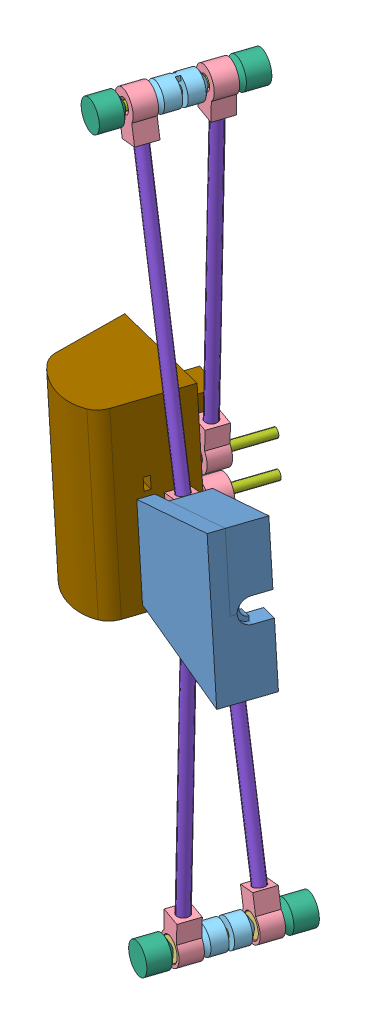
SolidWorks assembly leg_assembly2, configuration Default. Lengths in mm.
Overall size (107 250.56 70.48).
36 component instances, 9 part files, 82 mates.
Components (placement in the parent):
- Hips1-1: Hips1 [Default] at (-2.4449 -56.3028 130.8547) x (-0.09987 0.994445 -0.033239) z (-0.943557 -0.105257 -0.31404) size (50 17 40)
- RodHipJoint-1: RodHipJoint [Default] at (7.4351 -34.7879 113.0643) x (-0.917565 -0.254583 -0.305389) z (-0.241555 0.967051 -0.080396) size (3 18 3)
- RodHipJoint-2: RodHipJoint [Default] at (8.6335 -46.7213 113.4632) x (-0.917565 -0.254583 -0.305389) z (-0.241555 0.967051 -0.080396) size (3 18 3)
- bushing-3: bushing [Default] at (-17.889 -38.1572 88.3526) x (0.920506 0.242503 0.306368) z (-0.230094 0.970151 -0.076581) size (7.5 5 7.5)
- LegConnector1-4: LegConnector1 [Default] at (-19.8153 -38.1572 94.1404) x (0.948274 -0.034168 0.31561) z (0.032419 0.999416 0.01079) size (10 7 15)
- bushing-5: bushing [Default] at (6.4546 -46.7213 120.0101) x (0.948828 0 0.315794) z (0 1 0) size (7.5 5 7.5)
- LegConnector1-6: LegConnector1 [Default] at (-18.6169 -50.0905 94.5393) x (-0.920475 -0.242632 -0.306358) z (0.230216 -0.970118 0.076622) size (10 7 15)
- LegConnector1-7: LegConnector1 [Default] at (4.5282 -46.7213 125.7979) x (-0.948274 0.034168 -0.31561) z (-0.032419 -0.999416 -0.01079) size (10 7 15)
- bushing-6: bushing [Default] at (-16.6905 -50.0905 88.7514) x (0.920506 0.242503 0.306368) z (-0.230094 0.970151 -0.076581) size (7.5 5 7.5)
- KneeConnectorSpringSpacer-1: KneeConnectorSpringSpacer [Default] at (8.4422 -166.2192 103.3872) x (-0.116707 0.992407 -0.038843) z (-0.315794 0 0.948828) size (9.2 9.2 7.75)
- KneeEndConnector-1: KneeEndConnector [Default] at (0.2158 -161.6541 126.3124) x (0.948569 0.023349 0.315708) z (-0.315794 0 0.948828) size (10 10 9)
- LegConnector1-8: LegConnector1 [Default] at (3.0106 -161.6541 117.9153) x (-0.948274 0.034168 -0.31561) z (0.032419 0.999416 0.01079) size (10 7 15)
- ScrewThread-1: ScrewThread [Default] at (-1.3632 -161.6541 131.0566) x (0.948569 0.023349 0.315708) z (-0.022154 0.999727 -0.007373) size (3 43.5 3)
- KneeConnectorSpringSpacer-2: KneeConnectorSpringSpacer [Default] at (3.5474 -166.2192 118.094) x (-0.116707 0.992407 -0.038843) z (0.315794 0 -0.948828) size (9.2 9.2 7.75)
- KneeEndConnector-2: KneeEndConnector [Default] at (10.7949 -161.6541 94.5267) x (-0.209228 0.975384 -0.069636) z (0.315794 0 -0.948828) size (10 10 9)
- LegConnector1-9: LegConnector1 [Default] at (10.0686 -161.6541 96.709) x (-0.920475 -0.242632 -0.306358) z (-0.230216 0.970118 -0.076622) size (10 7 15)
- bushing-7: bushing [Default] at (1.0842 -161.6541 123.7032) x (0.948569 0.023349 0.315708) z (0.022154 -0.999727 0.007373) size (7.5 5 7.5)
- bushing-8: bushing [Default] at (8.1422 -161.6541 102.4969) x (-0.867734 -0.404513 -0.288804) z (-0.383813 0.914532 -0.127743) size (7.5 5 7.5)
- LegCarbon-6: LegCarbon [Default] at (2.0674 -156.6571 121.2902) x (0.955109 -0.034159 0.294278) z (-0.294475 -0.000765 0.955659) size (4 105 4)
- LegConnector1-10: LegConnector1 [Default] at (3.3298 -34.7879 125.3991) x (0.920475 0.242632 0.306358) z (-0.230216 0.970118 -0.076622) size (10 7 15)
- LegCarbon-7: LegCarbon [Default] at (3.284 -29.9374 121.6951) x (0.95056 0.207314 -0.231205) z (0.208412 0.126061 0.969883) size (4 105 4)
- LegCarbon-8: LegCarbon [Default] at (-15.1439 71.7786 92.0064) x (-0.857287 0.033355 -0.513757) z (-0.513817 0.007406 0.857868) size (4 105 4)
- bushing-9: bushing [Default] at (5.2561 -34.7879 119.6112) x (0.948828 0 0.315794) z (0 1 0) size (7.5 5 7.5)
- bushing-10: bushing [Default] at (-21.2188 76.7757 110.7997) x (-0.871511 0.39539 -0.290061) z (-0.375157 -0.918513 -0.124862) size (7.5 5 7.5)
- ScrewThread-2: ScrewThread [Default] at (-11.7134 76.7757 82.24) x (0.948743 -0.013397 0.315766) z (-0.012712 -0.99991 -0.004231) size (3 43.5 3)
- KneeEndConnector-3: KneeEndConnector [Default] at (-23.8714 76.7757 118.7699) x (-0.948413 0.029578 -0.315656) z (-0.315794 0 0.948828) size (10 10 9)
- KneeConnectorSpringSpacer-3: KneeConnectorSpringSpacer [Default] at (-16.624 81.3407 95.2026) x (0.116707 -0.992407 0.038843) z (-0.315794 0 0.948828) size (9.2 9.2 7.75)
- bushing-11: bushing [Default] at (-14.1608 76.7757 89.5934) x (0.948743 -0.013397 0.315766) z (0.012712 0.99991 0.004231) size (7.5 5 7.5)
- LegConnector1-11: LegConnector1 [Default] at (-23.1451 76.7757 116.5876) x (-0.920475 -0.242632 -0.306358) z (0.230216 -0.970118 0.076622) size (10 7 15)
- KneeConnectorSpringSpacer-4: KneeConnectorSpringSpacer [Default] at (-21.5188 81.3407 109.9094) x (0.116707 -0.992407 0.038843) z (0.315794 0 -0.948828) size (9.2 9.2 7.75)
- KneeEndConnector-4: KneeEndConnector [Default] at (-13.2923 76.7757 86.9841) x (0.948743 -0.013397 0.315766) z (0.315794 0 -0.948828) size (10 10 9)
- LegConnector1-12: LegConnector1 [Default] at (-16.0871 76.7757 95.3813) x (-0.948274 0.034168 -0.31561) z (-0.032419 -0.999416 -0.01079) size (10 7 15)
- LegCarbon-9: LegCarbon [Default] at (7.8122 -156.8035 99.6468) x (-0.918825 -0.190756 0.345503) z (-0.320562 -0.149942 -0.935284) size (4 105 4)
- foot2-1: foot2 [Default] at (-48.9325 -77.5359 86.5573) x (0.943557 0.105257 0.31404) z (-0.315794 0 0.948828) size (40 60 41.96)
- ScrewThread-3: ScrewThread [Default] at (-13.0257 -38.1572 73.7406) x (0.948828 0 0.315794) z (0 -1 0) size (3 43.5 3)
- ScrewThread-4: ScrewThread [Default] at (-11.8273 -50.0905 74.1395) x (0.948828 0 0.315794) z (0 -1 0) size (3 43.5 3)
Mates (geometry in assembly coordinates):
- Coincident1: coincident anti-aligned: plane of Hips1-1 through (1.7508 -34.7879 130.1432) normal (0.315794 0 -0.948828); plane of RodHipJoint-1 through (1.7508 -34.7879 130.1432) normal (-0.315794 0 0.948828)
- Concentric1: concentric aligned: cylinder of Hips1-1 through (1.7508 -34.7879 130.1432) axis (0.315794 0 -0.948828) radius 1.55; cylinder of RodHipJoint-1 through (1.7508 -34.7879 130.1432) axis (0.315794 0 -0.948828) radius 1.5
- Coincident2: coincident anti-aligned: plane of Hips1-1 through (2.9492 -46.7213 130.5421) normal (0.315794 0 -0.948828); plane of RodHipJoint-2 through (2.9492 -46.7213 130.5421) normal (-0.315794 0 0.948828)
- Concentric2: concentric aligned: cylinder of Hips1-1 through (2.9492 -46.7213 130.5421) axis (0.315794 0 -0.948828) radius 1.55; cylinder of RodHipJoint-2 through (2.9492 -46.7213 130.5421) axis (0.315794 0 -0.948828) radius 1.5
- Concentric5: concentric anti-aligned: cylinder of bushing-3 through (-19.2311 -38.1572 92.3851) axis (0.315794 0 -0.948828) radius 2.25; cylinder of LegConnector1-4 through (-17.6048 -38.1572 87.4986) axis (-0.315794 0 0.948828) radius 2.4
- Coincident5: coincident anti-aligned: plane of bushing-3 through (-17.889 -38.1572 88.3526) normal (-0.315794 0 0.948828); plane of LegConnector1-4 through (-17.889 -38.1572 88.3526) normal (0.315794 0 -0.948828)
- Concentric11: concentric anti-aligned: cylinder of bushing-5 through (5.1124 -46.7213 124.0426) axis (0.315794 0 -0.948828) radius 2.25; cylinder of LegConnector1-7 through (6.7388 -46.7213 119.1562) axis (-0.315794 0 0.948828) radius 2.4
- Coincident14: coincident anti-aligned: plane of bushing-5 through (6.4546 -46.7213 120.0101) normal (-0.315794 0 0.948828); plane of LegConnector1-7 through (6.4546 -46.7213 120.0101) normal (0.315794 0 -0.948828)
- Concentric12: concentric anti-aligned: cylinder of LegConnector1-6 through (-16.4063 -50.0905 87.8975) axis (-0.315794 0 0.948828) radius 2.4; cylinder of bushing-6 through (-18.0327 -50.0905 92.784) axis (0.315794 0 -0.948828) radius 2.25
- Coincident16: coincident anti-aligned: plane of LegConnector1-6 through (-16.6905 -50.0905 88.7514) normal (0.315794 0 -0.948828); plane of bushing-6 through (-16.6905 -50.0905 88.7514) normal (-0.315794 0 0.948828)
- Coincident32: coincident anti-aligned: plane of LegConnector1-8 through (1.0842 -161.6541 123.7032) normal (-0.315794 0 0.948828); plane of bushing-7 through (1.0842 -161.6541 123.7032) normal (0.315794 0 -0.948828)
- Concentric28: concentric anti-aligned: cylinder of LegConnector1-8 through (0.8 -161.6541 124.5571) axis (0.315794 0 -0.948828) radius 2.4; cylinder of bushing-7 through (2.4263 -161.6541 119.6706) axis (-0.315794 0 0.948828) radius 2.25
- Coincident33: coincident anti-aligned: plane of LegConnector1-9 through (8.1422 -161.6541 102.4969) normal (-0.315794 0 0.948828); plane of bushing-8 through (8.1422 -161.6541 102.4969) normal (0.315794 0 -0.948828)
- Concentric29: concentric anti-aligned: cylinder of LegConnector1-9 through (7.858 -161.6541 103.3508) axis (0.315794 0 -0.948828) radius 2.4; cylinder of bushing-8 through (9.4843 -161.6541 98.4643) axis (-0.315794 0 0.948828) radius 2.25
- Coincident34: coincident anti-aligned: plane of KneeEndConnector-1 through (-1.3632 -161.6541 131.0566) normal (0.315794 0 -0.948828); plane of ScrewThread-1 through (-1.3632 -161.6541 131.0566) normal (-0.315794 0 0.948828)
- Concentric30: concentric anti-aligned: cylinder of KneeEndConnector-1 through (0.2158 -161.6541 126.3124) axis (0.315794 0 -0.948828) radius 1.55; cylinder of ScrewThread-1 through (12.3739 -161.6541 89.7826) axis (-0.315794 0 0.948828) radius 1.5
- Coincident35: coincident anti-aligned: circle of KneeEndConnector-1; plane of bushing-7 through (0.8474 -161.6541 124.4148) normal (-0.315794 0 0.948828)
- Concentric31: concentric anti-aligned: cylinder of LegConnector1-8 through (0.8 -161.6541 124.5571) axis (0.315794 0 -0.948828) radius 2.4; cylinder of ScrewThread-1 through (12.3739 -161.6541 89.7826) axis (-0.315794 0 0.948828) radius 1.5
- Concentric32: concentric anti-aligned: circle of LegConnector1-8; circle of KneeConnectorSpringSpacer-2
- Concentric33: concentric anti-aligned: cylinder of ScrewThread-1 through (12.3739 -161.6541 89.7826) axis (-0.315794 0 0.948828) radius 1.5; circle of KneeConnectorSpringSpacer-2
- Coincident36: coincident aligned: plane of LegConnector1-8 through (3.0106 -161.6541 117.9153) normal (0.315794 0 -0.948828); circle of KneeConnectorSpringSpacer-2
- Coincident37: coincident anti-aligned: plane of KneeConnectorSpringSpacer-1 through (5.458 -161.6541 110.5619) normal (-0.315794 0 0.948828); plane of KneeConnectorSpringSpacer-2 through (5.458 -161.6541 110.5619) normal (0.315794 0 -0.948828)
- Concentric35: concentric aligned: cylinder of KneeConnectorSpringSpacer-1 through (7.9054 -161.6541 103.2085) axis (-0.315794 0 0.948828) radius 1.55; cylinder of ScrewThread-1 through (12.3739 -161.6541 89.7826) axis (-0.315794 0 0.948828) radius 1.5
- Coincident39: coincident anti-aligned: line of KneeConnectorSpringSpacer-1 through (4.8592 -164.6922 110.3626) axis (0.116707 -0.992407 0.038843); line of KneeConnectorSpringSpacer-2 through (5.0404 -166.233 110.4229) axis (-0.116707 0.992407 -0.038843)
- Coincident41: coincident aligned: circle of KneeConnectorSpringSpacer-1; plane of bushing-8 through (7.9054 -161.6541 103.2085) normal (-0.315794 0 0.948828)
- Concentric36: concentric anti-aligned: cylinder of ScrewThread-1 through (12.3739 -161.6541 89.7826) axis (-0.315794 0 0.948828) radius 1.5; cylinder of bushing-8 through (7.9054 -161.6541 103.2085) axis (0.315794 0 -0.948828) radius 1.5
- Coincident42: coincident anti-aligned: plane of ScrewThread-1 through (12.3739 -161.6541 89.7826) normal (0.315794 0 -0.948828); plane of KneeEndConnector-2 through (12.3739 -161.6541 89.7826) normal (-0.315794 0 0.948828)
- Concentric37: concentric aligned: cylinder of ScrewThread-1 through (12.3739 -161.6541 89.7826) axis (-0.315794 0 0.948828) radius 1.5; cylinder of KneeEndConnector-2 through (10.7949 -161.6541 94.5267) axis (-0.315794 0 0.948828) radius 1.55
- Coincident44: coincident anti-aligned: plane of LegConnector1-8 through (3.1727 -156.6571 117.9693) normal (0.032419 0.999416 0.01079); plane of LegCarbon-6 through (2.0674 -156.6571 121.2902) normal (-0.032419 -0.999416 -0.01079)
- Concentric39: concentric aligned: cylinder of LegConnector1-8 through (2.2295 -151.66 121.3441) axis (-0.032419 -0.999416 -0.01079) radius 2.1; cylinder of LegCarbon-6 through (5.4714 -51.7184 122.4231) axis (-0.032419 -0.999416 -0.01079) radius 2
- Coincident46: coincident anti-aligned: plane of LegConnector1-10 through (5.2561 -34.7879 119.6112) normal (0.315794 0 -0.948828); plane of bushing-9 through (5.2561 -34.7879 119.6112) normal (-0.315794 0 0.948828)
- Coincident47: coincident anti-aligned: plane of LegConnector1-10 through (2.1787 -29.9374 125.016) normal (-0.230216 0.970118 -0.076622); plane of LegCarbon-7 through (3.284 -29.9374 121.6951) normal (0.230216 -0.970118 0.076622)
- Coincident48: coincident anti-aligned: plane of bushing-11 through (-13.9239 76.7757 88.8818) normal (0.315794 0 -0.948828); circle of KneeEndConnector-4
- Coincident49: coincident anti-aligned: line of KneeConnectorSpringSpacer-3 through (-20.0001 81.1086 102.2469) axis (0.116707 -0.992407 0.038843); line of KneeConnectorSpringSpacer-4 through (-19.8189 79.5677 102.3072) axis (-0.116707 0.992407 -0.038843)
- Coincident50: coincident anti-aligned: plane of KneeConnectorSpringSpacer-3 through (-18.5345 76.7757 102.7347) normal (-0.315794 0 0.948828); plane of KneeConnectorSpringSpacer-4 through (-18.5345 76.7757 102.7347) normal (0.315794 0 -0.948828)
- Coincident51: coincident aligned: circle of KneeConnectorSpringSpacer-3; plane of LegConnector1-12 through (-16.0871 76.7757 95.3813) normal (-0.315794 0 0.948828)
- Coincident52: coincident anti-aligned: plane of ScrewThread-2 through (-11.7134 76.7757 82.24) normal (0.315794 0 -0.948828); plane of KneeEndConnector-4 through (-11.7134 76.7757 82.24) normal (-0.315794 0 0.948828)
- Concentric44: concentric anti-aligned: cylinder of ScrewThread-2 through (-25.4504 76.7757 123.514) axis (0.315794 0 -0.948828) radius 1.5; circle of KneeConnectorSpringSpacer-3
- Concentric45: concentric anti-aligned: cylinder of ScrewThread-2 through (-25.4504 76.7757 123.514) axis (0.315794 0 -0.948828) radius 1.5; cylinder of KneeEndConnector-4 through (-13.2923 76.7757 86.9841) axis (-0.315794 0 0.948828) radius 1.55
- Concentric46: concentric anti-aligned: cylinder of bushing-10 through (-20.9819 76.7757 110.0881) axis (-0.315794 0 0.948828) radius 1.5; cylinder of ScrewThread-2 through (-25.4504 76.7757 123.514) axis (0.315794 0 -0.948828) radius 1.5
- Concentric47: concentric anti-aligned: cylinder of bushing-11 through (-15.5029 76.7757 93.6259) axis (0.315794 0 -0.948828) radius 2.25; cylinder of LegConnector1-12 through (-13.8765 76.7757 88.7395) axis (-0.315794 0 0.948828) radius 2.4
- Concentric48: concentric aligned: cylinder of ScrewThread-2 through (-25.4504 76.7757 123.514) axis (0.315794 0 -0.948828) radius 1.5; cylinder of KneeConnectorSpringSpacer-4 through (-20.9819 76.7757 110.0881) axis (0.315794 0 -0.948828) radius 1.55
- Concentric49: concentric aligned: cylinder of LegCarbon-8 through (-18.5479 -33.1601 90.8735) axis (0.032419 0.999416 0.01079) radius 2; cylinder of LegConnector1-12 through (-15.306 66.7815 91.9525) axis (0.032419 0.999416 0.01079) radius 2.1
- Concentric50: concentric aligned: cylinder of ScrewThread-2 through (-25.4504 76.7757 123.514) axis (0.315794 0 -0.948828) radius 1.5; cylinder of KneeEndConnector-3 through (-23.8714 76.7757 118.7699) axis (0.315794 0 -0.948828) radius 1.55
- Concentric51: concentric anti-aligned: cylinder of LegCarbon-7 through (-20.8887 71.9251 113.6498) axis (0.230216 -0.970118 0.076622) radius 2; cylinder of LegConnector1-11 through (-19.7377 67.0745 114.0329) axis (-0.230216 0.970118 -0.076622) radius 2.1
- Coincident53: coincident anti-aligned: plane of ScrewThread-2 through (-25.4504 76.7757 123.514) normal (-0.315794 0 0.948828); plane of KneeEndConnector-3 through (-25.4504 76.7757 123.514) normal (0.315794 0 -0.948828)
- Coincident54: coincident aligned: plane of bushing-10 through (-20.9819 76.7757 110.0881) normal (0.315794 0 -0.948828); circle of KneeConnectorSpringSpacer-4
- Coincident55: coincident anti-aligned: plane of LegCarbon-7 through (-20.8887 71.9251 113.6498) normal (-0.230216 0.970118 -0.076622); plane of LegConnector1-11 through (-21.994 71.9251 116.9707) normal (0.230216 -0.970118 0.076622)
- Coincident56: coincident anti-aligned: plane of LegCarbon-8 through (-15.1439 71.7786 92.0064) normal (0.032419 0.999416 0.01079); plane of LegConnector1-12 through (-16.2492 71.7786 95.3273) normal (-0.032419 -0.999416 -0.01079)
- Concentric52: concentric anti-aligned: cylinder of bushing-10 through (-22.5609 76.7757 114.8322) axis (0.315794 0 -0.948828) radius 2.25; cylinder of LegConnector1-11 through (-20.9345 76.7757 109.9458) axis (-0.315794 0 0.948828) radius 2.4
- Coincident57: coincident anti-aligned: plane of bushing-11 through (-14.1608 76.7757 89.5934) normal (-0.315794 0 0.948828); plane of LegConnector1-12 through (-14.1608 76.7757 89.5934) normal (0.315794 0 -0.948828)
- Coincident58: coincident anti-aligned: plane of bushing-10 through (-21.2188 76.7757 110.7997) normal (-0.315794 0 0.948828); plane of LegConnector1-11 through (-21.2188 76.7757 110.7997) normal (0.315794 0 -0.948828)
- Concentric53: concentric anti-aligned: cylinder of LegConnector1-10 through (5.5403 -34.7879 118.7573) axis (-0.315794 0 0.948828) radius 2.4; cylinder of bushing-9 through (3.914 -34.7879 123.6437) axis (0.315794 0 -0.948828) radius 2.25
- Concentric54: concentric aligned: cylinder of LegConnector1-10 through (2.1329 -25.0868 121.312) axis (0.230216 -0.970118 0.076622) radius 2.1; cylinder of LegCarbon-7 through (-20.8887 71.9251 113.6498) axis (0.230216 -0.970118 0.076622) radius 2
- Concentric55: concentric anti-aligned: cylinder of ScrewThread-2 through (-25.4504 76.7757 123.514) axis (0.315794 0 -0.948828) radius 1.5; cylinder of LegConnector1-12 through (-13.8765 76.7757 88.7395) axis (-0.315794 0 0.948828) radius 2.4
- Concentric56: concentric anti-aligned: circle of KneeConnectorSpringSpacer-3; circle of LegConnector1-12
- Concentric59: concentric anti-aligned: cylinder of LegConnector1-4 through (-18.3858 -28.163 90.9274) axis (-0.032419 -0.999416 -0.01079) radius 2.1; cylinder of LegCarbon-8 through (-18.5479 -33.1601 90.8735) axis (0.032419 0.999416 0.01079) radius 2
- Coincident62: coincident anti-aligned: plane of LegConnector1-4 through (-19.6532 -33.1601 94.1944) normal (0.032419 0.999416 0.01079); plane of LegCarbon-8 through (-18.5479 -33.1601 90.8735) normal (-0.032419 -0.999416 -0.01079)
- Parallel9: parallel anti-aligned: line of LegConnector1-10 through (6.4598 -24.2375 119.0633) axis (-0.920475 -0.242632 -0.306358); line of LegConnector1-11 through (-21.854 66.2253 109.6397) axis (0.920475 0.242632 0.306358)
- Parallel10: parallel anti-aligned: line of LegConnector1-4 through (-13.9616 -28.2826 88.7112) axis (-0.948274 0.034168 -0.31561); line of LegConnector1-12 through (-17.5197 66.9011 87.5269) axis (0.948274 -0.034168 0.31561)
- Concentric63: concentric anti-aligned: cylinder of LegConnector1-7 through (5.3093 -56.7154 122.3692) axis (0.032419 0.999416 0.01079) radius 2.1; cylinder of LegCarbon-6 through (5.4714 -51.7184 122.4231) axis (-0.032419 -0.999416 -0.01079) radius 2
- Parallel11: parallel anti-aligned: line of LegConnector1-7 through (3.0956 -56.5959 117.9436) axis (0.948274 -0.034168 0.31561); line of LegConnector1-8 through (6.6537 -151.7796 119.1278) axis (-0.948274 0.034168 -0.31561)
- Coincident68: coincident anti-aligned: plane of LegConnector1-7 through (4.3661 -51.7184 125.744) normal (-0.032419 -0.999416 -0.01079); plane of LegCarbon-6 through (5.4714 -51.7184 122.4231) normal (0.032419 0.999416 0.01079)
- Parallel13: parallel anti-aligned: line of LegConnector1-6 through (-17.3258 -60.6409 87.5915) axis (0.920475 0.242632 0.306358); line of LegConnector1-9 through (10.9881 -151.1037 97.015) axis (-0.920475 -0.242632 -0.306358)
- Concentric68: concentric anti-aligned: cylinder of LegConnector1-6 through (-15.2094 -59.7917 91.9846) axis (-0.230216 0.970118 -0.076622) radius 2.1; cylinder of LegCarbon-9 through (-16.3605 -54.9411 91.6015) axis (0.230216 -0.970118 0.076622) radius 2
- Coincident71: coincident anti-aligned: plane of LegConnector1-9 through (8.9175 -156.8035 96.3259) normal (-0.230216 0.970118 -0.076622); plane of LegCarbon-9 through (7.8122 -156.8035 99.6468) normal (0.230216 -0.970118 0.076622)
- Concentric69: concentric aligned: cylinder of LegConnector1-9 through (6.6611 -151.953 99.2637) axis (0.230216 -0.970118 0.076622) radius 2.1; cylinder of LegCarbon-9 through (-16.3605 -54.9411 91.6015) axis (0.230216 -0.970118 0.076622) radius 2
- Coincident72: coincident anti-aligned: plane of LegConnector1-6 through (-17.4658 -54.9411 94.9224) normal (0.230216 -0.970118 0.076622); plane of LegCarbon-9 through (-16.3605 -54.9411 91.6015) normal (-0.230216 0.970118 -0.076622)
- Concentric70: concentric anti-aligned: cylinder of RodHipJoint-2 through (2.9492 -46.7213 130.5421) axis (0.315794 0 -0.948828) radius 1.5; cylinder of bushing-5 through (6.6914 -46.7213 119.2985) axis (-0.315794 0 0.948828) radius 1.5
- Concentric74: concentric anti-aligned: cylinder of RodHipJoint-1 through (1.7508 -34.7879 130.1432) axis (0.315794 0 -0.948828) radius 1.5; cylinder of bushing-9 through (5.493 -34.7879 118.8996) axis (-0.315794 0 0.948828) radius 1.5
- Distance2: distance = 2 mm anti-aligned: plane of LegConnector1-7 through (4.5282 -46.7213 125.7979) normal (-0.315794 0 0.948828); plane of Hips1-1 through (-0.8659 -56.3028 126.1105) normal (0.315794 0 -0.948828)
- LimitAngle4: limit planar angle = 3.001966 rad aligned: line of LegConnector1-7 through (3.3041 -50.1703 118.013) axis (-0.032419 -0.999416 -0.01079); line of Hips1-1 through (-0.8659 -56.3028 126.1105) axis (-0.09987 0.994445 -0.033239)
- LimitAngle5: limit planar angle = 0.139626 rad aligned: line of LegConnector1-10 through (1.4966 -32.1731 117.4114) axis (-0.230216 0.970118 -0.076622); line of Hips1-1 through (-0.8659 -56.3028 126.1105) axis (-0.09987 0.994445 -0.033239)
- Coincident73: coincident anti-aligned: plane of foot2-1 through (-26.7628 -38.1572 115.0146) normal (0.315794 0 -0.948828); plane of ScrewThread-3 through (-26.7628 -38.1572 115.0146) normal (-0.315794 0 0.948828)
- Concentric75: concentric aligned: cylinder of foot2-1 through (-26.7628 -38.1572 115.0146) axis (0.315794 0 -0.948828) radius 1.6; cylinder of ScrewThread-3 through (-26.7628 -38.1572 115.0146) axis (0.315794 0 -0.948828) radius 1.5
- Coincident74: coincident anti-aligned: plane of foot2-1 through (-25.5643 -50.0905 115.4135) normal (0.315794 0 -0.948828); plane of ScrewThread-4 through (-25.5643 -50.0905 115.4135) normal (-0.315794 0 0.948828)
- Concentric76: concentric aligned: cylinder of foot2-1 through (-25.5643 -50.0905 115.4135) axis (0.315794 0 -0.948828) radius 1.6; cylinder of ScrewThread-4 through (-25.5643 -50.0905 115.4135) axis (0.315794 0 -0.948828) radius 1.5
- Concentric77: concentric anti-aligned: cylinder of bushing-6 through (-16.4537 -50.0905 88.0398) axis (-0.315794 0 0.948828) radius 1.5; cylinder of ScrewThread-4 through (-25.5643 -50.0905 115.4135) axis (0.315794 0 -0.948828) radius 1.5
- Concentric78: concentric anti-aligned: cylinder of bushing-3 through (-17.6521 -38.1572 87.6409) axis (-0.315794 0 0.948828) radius 1.5; cylinder of ScrewThread-3 through (-26.7628 -38.1572 115.0146) axis (0.315794 0 -0.948828) radius 1.5
- Coincident76: coincident aligned: plane of LegConnector1-4 through (-19.8153 -38.1572 94.1404) normal (-0.315794 0 0.948828); circle of foot2-1
- Coincident77: coincident aligned: plane of LegConnector1-6 through (-18.6169 -50.0905 94.5393) normal (-0.315794 0 0.948828); circle of foot2-1
- Parallel14: parallel anti-aligned: line of Hips1-1 through (-0.8659 -56.3028 126.1105) axis (-0.09987 0.994445 -0.033239); line of foot2-1 through (-17.1825 -13.659 97.1246) axis (0.09987 -0.994445 0.033239)
